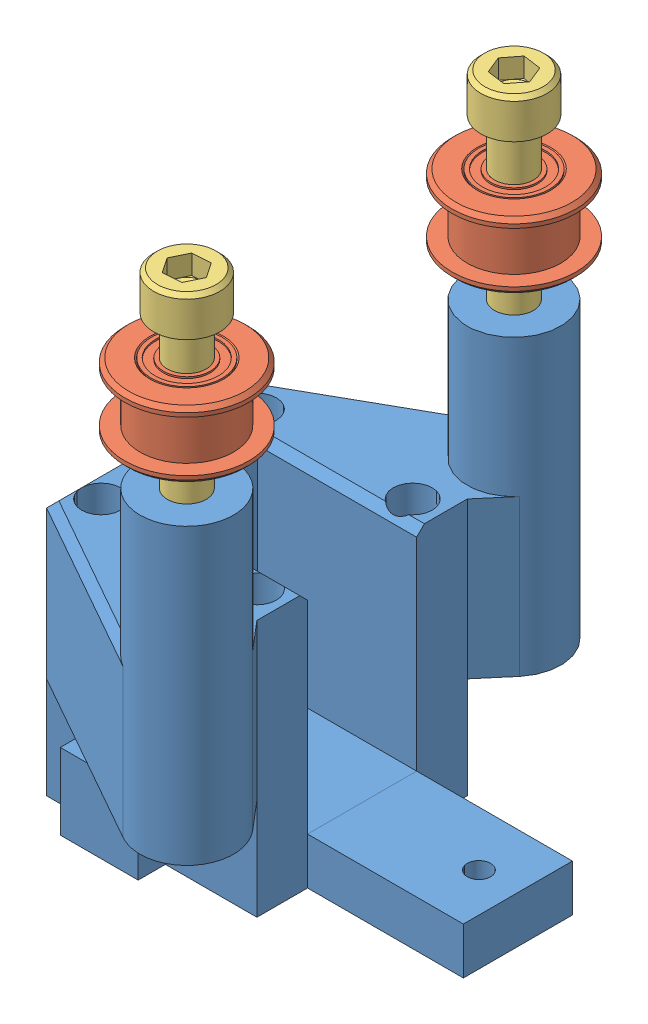
SolidWorks assembly rail to rail sliding idler mount assembly, configuration Default. Lengths in mm.
Overall size (47 76.2 59.95).
5 component instances, 3 part files, 8 mates.
Components (placement in the parent):
- rail rail mount-1: rail rail mount [Default] at origin size (47 50.7 58)
- GT2 idler pulley (5 mm bore) v1-1: GT2 idler pulley (5 mm bore) v1 [Default] at (12 64.2 -21) x (1 0 0) z (0 -1 0) size (15.9 15.9 8.5)
- GT2 idler pulley (5 mm bore) v1-2: GT2 idler pulley (5 mm bore) v1 [Default] at (12 64.2 21) x (1 0 0) z (0 -1 0) size (15.9 15.9 8.5)
- socket head cap screw_am-1: socket head cap screw_am [B18.3.1M - 5 x 0.8 x 50 Hex SHCS -- 22NHX] at (12 76.2 -21) x (0 -1 0) z (0.1365 0 -0.99064) size (55 8.5 8.5)
- socket head cap screw_am-2: socket head cap screw_am [B18.3.1M - 5 x 0.8 x 50 Hex SHCS -- 22NHX] at (12 75.2 21) x (0 -1 0) z (0.069117 0 0.997609) size (55 8.5 8.5)
Mates (geometry in assembly coordinates):
- Concentric1: concentric aligned: cylinder of rail rail mount-1 through (12 50.7 -21) axis (0 -1 0) radius 6; cylinder of GT2 idler pulley (5 mm bore) v1-1 through (12 64.2 -21) axis (0 -1 0) radius 6
- Distance1: distance = 6 mm anti-aligned: plane of GT2 idler pulley (5 mm bore) v1-1 through (12 56.7 -21) normal (0 -1 0); plane of rail rail mount-1 through (12 50.7 -21) normal (0 1 0)
- Concentric2: concentric aligned: cylinder of rail rail mount-1 through (12 50.7 21) axis (0 -1 0) radius 6; cylinder of GT2 idler pulley (5 mm bore) v1-2 through (12 64.2 21) axis (0 -1 0) radius 6
- Coincident1: coincident aligned: plane of GT2 idler pulley (5 mm bore) v1-1 through (12 65.2 -21) normal (0 1 0); plane of GT2 idler pulley (5 mm bore) v1-2 through (12 65.2 21) normal (0 1 0)
- Concentric3: concentric anti-aligned: cylinder of GT2 idler pulley (5 mm bore) v1-1 through (12 64.2 -21) axis (0 -1 0) radius 2.5; cylinder of socket head cap screw_am-1 through (12 107.95 -21) axis (0 1 0) radius 4.25
- Concentric4: concentric anti-aligned: cylinder of GT2 idler pulley (5 mm bore) v1-2 through (12 64.2 21) axis (0 -1 0) radius 2.5; cylinder of socket head cap screw_am-2 through (12 106.95 21) axis (0 1 0) radius 4.25
- Distance2: distance = 6 mm anti-aligned: plane of GT2 idler pulley (5 mm bore) v1-1 through (12 65.2 -21) normal (0 1 0); plane of socket head cap screw_am-1 through (7.7898 71.2 -21.5801) normal (0 -1 0)
- Distance3: distance = 5 mm anti-aligned: plane of socket head cap screw_am-2 through (16.2398 70.2 20.7063) normal (0 -1 0); plane of GT2 idler pulley (5 mm bore) v1-2 through (12 65.2 21) normal (0 1 0)
